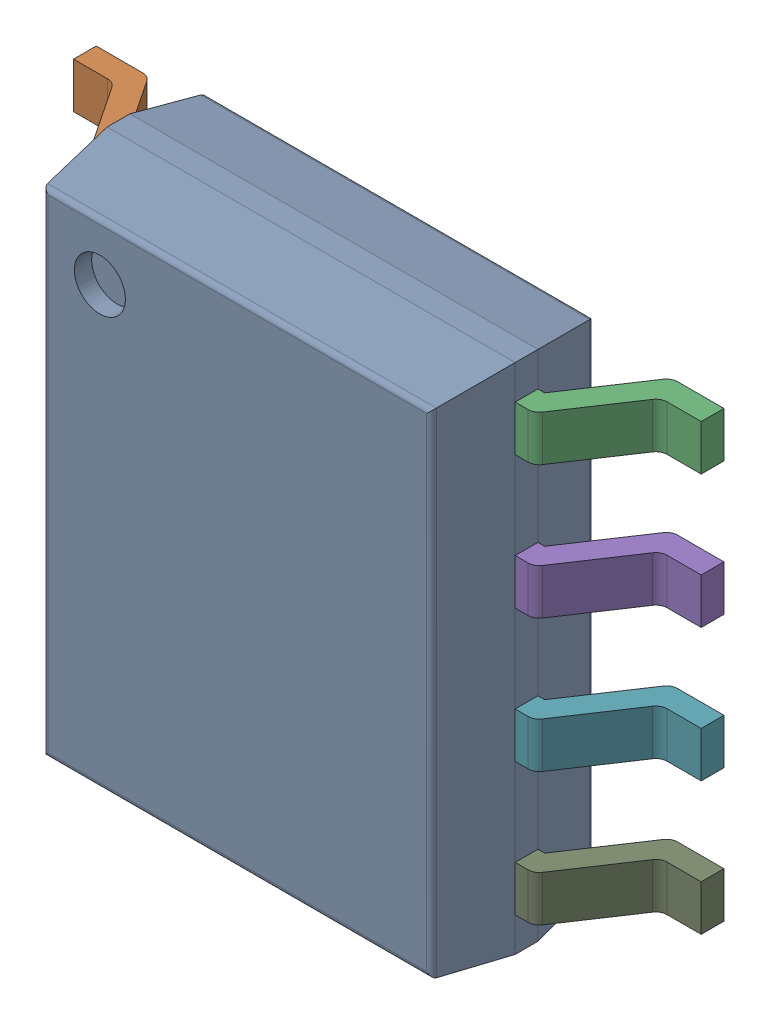
SolidWorks assembly 6348795168_1.step, configuration Default. Lengths in mm.
Overall size (6 4.9 1.65).
3 component instances, 3 part files, 0 mates.
Components (placement in the parent):
- Body-6_1.step-11: Body-6_1.step [Default] at origin size (3.9 4.9 1.55)
- PinsArrayLR_1.step-11: PinsArrayLR_1.step [Default] at origin size (6 4.24 0.95)
- ThermalPad_1.step-11: ThermalPad_1.step [Default] at (-1.045 -1.045 0) size (2.09 2.09 0.1)
